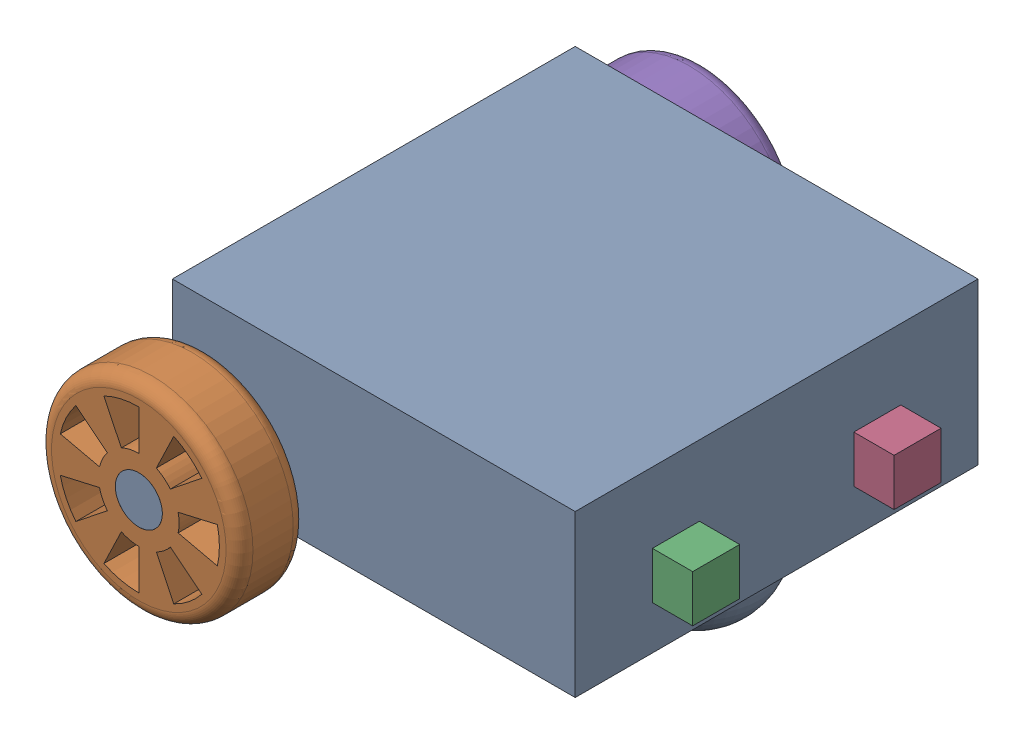
SolidWorks assembly nevil, configuration Default. Lengths in mm.
Overall size (370 170 420).
5 component instances, 3 part files, 11 mates.
Components (placement in the parent):
- Chesis-1: Chesis [Default] at origin size (320 170 420)
- Part2-1: Part2 [Default] at (-115 25 210) size (150 150 50)
- sensor-1: sensor [Default] at (180 50 75) x (0 0 1) z (0 -1 0) size (35 30 35)
- sensor-2: sensor [Default] at (180 50 -75) x (0 0 1) z (0 -1 0) size (35 30 35)
- Part2-2: Part2 [Default] at (-115 25 -160) size (150 150 50)
Mates (geometry in assembly coordinates):
- Concentric1: concentric anti-aligned: cylinder of Chesis-1 through (-115 25 210) axis (0 0 -1) radius 17.5; cylinder of Part2-1 through (-115 25 160) axis (0 0 1) radius 17.5
- Coincident1: coincident aligned: plane of Chesis-1 through (-115 25 210) normal (0 0 1); plane of Part2-1 through (-115 25 210) normal (0 0 1)
- Concentric2: concentric aligned: cylinder of Chesis-1 through (-115 25 -210) axis (0 0 1) radius 17.5; cylinder of Part2-2 through (-115 25 -210) axis (0 0 1) radius 17.5
- Coincident2: coincident aligned: plane of Chesis-1 through (-115 25 -210) normal (0 0 -1); plane of Part2-2 through (-115 25 -210) normal (0 0 -1)
- Concentric3: concentric aligned: cylinder of Chesis-1 through (170 50 75) axis (-1 0 0) radius 7.5; cylinder of sensor-1 through (170 50 75) axis (-1 0 0) radius 7.5
- Coincident3: coincident anti-aligned: plane of Chesis-1 through (170 50 75) normal (1 0 0); plane of sensor-1 through (170 50 75) normal (-1 0 0)
- Concentric4: concentric aligned: cylinder of Chesis-1 through (170 50 -75) axis (-1 0 0) radius 7.5; cylinder of sensor-2 through (170 50 -75) axis (-1 0 0) radius 7.5
- Coincident4: coincident anti-aligned: plane of Chesis-1 through (170 50 -75) normal (1 0 0); plane of sensor-2 through (170 50 -75) normal (-1 0 0)
- Parallel1: parallel aligned: plane of Chesis-1 through (-150 120 150) normal (0 0 1); plane of sensor-2 through (150 67.5 -57.5) normal (0 0 1)
- Parallel2: parallel aligned: plane of Chesis-1 through (-150 120 150) normal (0 0 1); plane of sensor-1 through (150 67.5 92.5) normal (0 0 1)
- Coincident7: coordinate: unknown of Chesis-1
